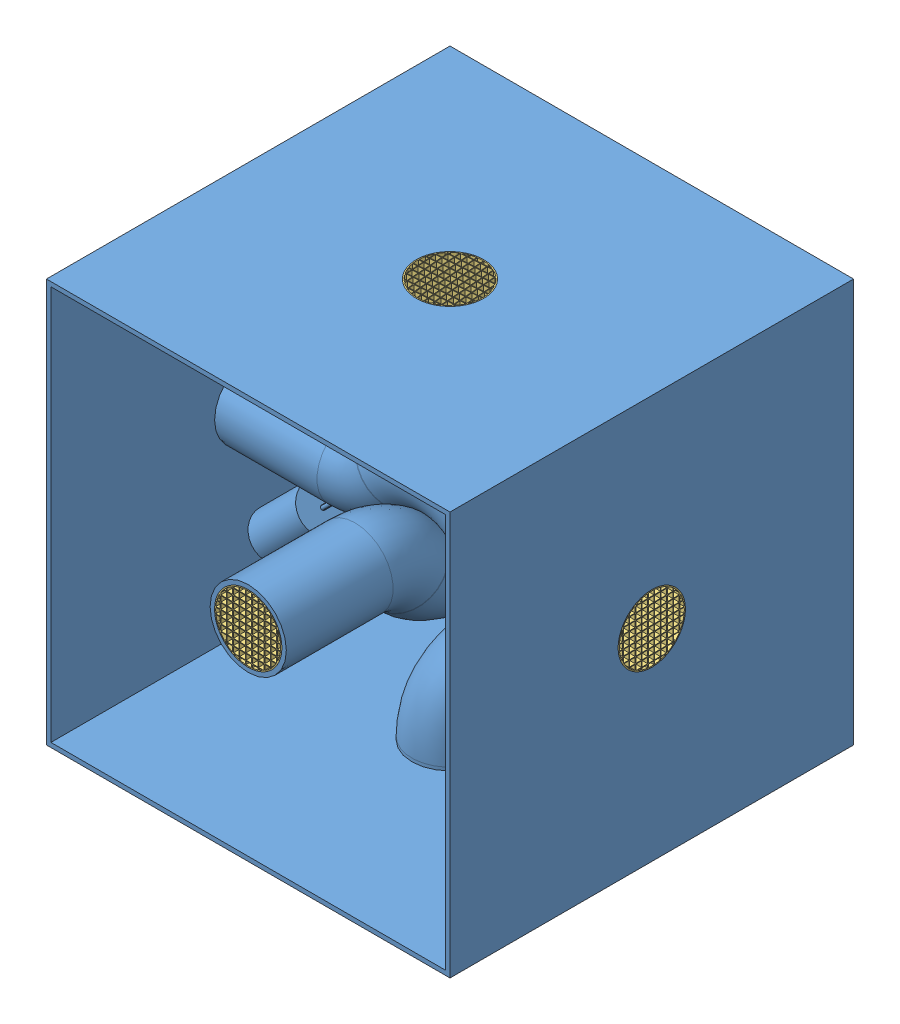
SolidWorks assembly propulsion design assembled, configuration Default. Lengths in mm.
Overall size (228.6 228.6 228.6).
10 component instances, 3 part files, 10 mates.
Components (placement in the parent):
- propulsion design 1-1: propulsion design 1 [Default] at (-141.4017 -124.1745 -93.2902) size (228.6 228.6 228.6)
- propeller-1: propeller [Default] at (-27.1017 -33.4596 6.4949) x (1 0 0) z (0 -0.707107 -0.707107) size (32.98 15.24 28.83)
- propeller-2: propeller [Default] at (-49.0741 6.2531 21.0098) x (0.707107 -0.707107 0) z (0 0 1) size (32.98 15.24 28.83)
- propeller-3: propeller [Default] at (20.8811 -2.2545 -26.973) size (32.98 15.24 28.83)
- flow straghtening device-1: flow straghtening device [Default] at (-128.7017 -9.8745 104.938) x (0 0 1) z (-1 0 0) size (38.1 38.1 12.7)
- flow straghtening device-2: flow straghtening device [Default] at (-110.9624 -6.5097 -80.5902) x (-0.999196 0.040092 0) z (0 0 -1) size (38.1 38.1 12.7)
- flow straghtening device-3: flow straghtening device [Default] at (56.6019 104.4255 14.8751) x (0.997325 0 -0.073095) z (0 -1 0) size (38.1 38.1 12.7)
- flow straghtening device-4: flow straghtening device [Default] at (56.8265 -9.8745 122.6098) size (38.1 38.1 12.7)
- flow straghtening device-5: flow straghtening device [Default] at (56.8265 -111.4745 21.0098) x (1 0 0) z (0 -1 0) size (38.1 38.1 12.7)
- flow straghtening device-6: flow straghtening device [Default] at (87.1983 -9.8745 104.938) x (0 0 1) z (-1 0 0) size (38.1 38.1 12.7)
Mates (geometry in assembly coordinates):
- Concentric1: concentric anti-aligned: circle of propulsion design 1-1; circle of propeller-1
- Concentric2: concentric aligned: circle of propulsion design 1-1; circle of propeller-2
- Concentric4: concentric aligned: circle of propulsion design 1-1; circle of propeller-3
- Coincident2: coincident anti-aligned: plane of propulsion design 1-1 through (20.8811 -9.8745 -26.973) normal (0 1 0); circle of propeller-3
- Coincident3: coincident anti-aligned: circle of propulsion design 1-1; circle of flow straghtening device-1
- Coincident4: coincident anti-aligned: circle of propulsion design 1-1; circle of flow straghtening device-5
- Coincident5: coincident aligned: circle of propulsion design 1-1; circle of flow straghtening device-4
- Coincident6: coincident anti-aligned: circle of propulsion design 1-1; circle of flow straghtening device-2
- Coincident7: coincident anti-aligned: circle of propulsion design 1-1; circle of flow straghtening device-6
- Coincident8: coincident anti-aligned: circle of propulsion design 1-1; circle of flow straghtening device-3
